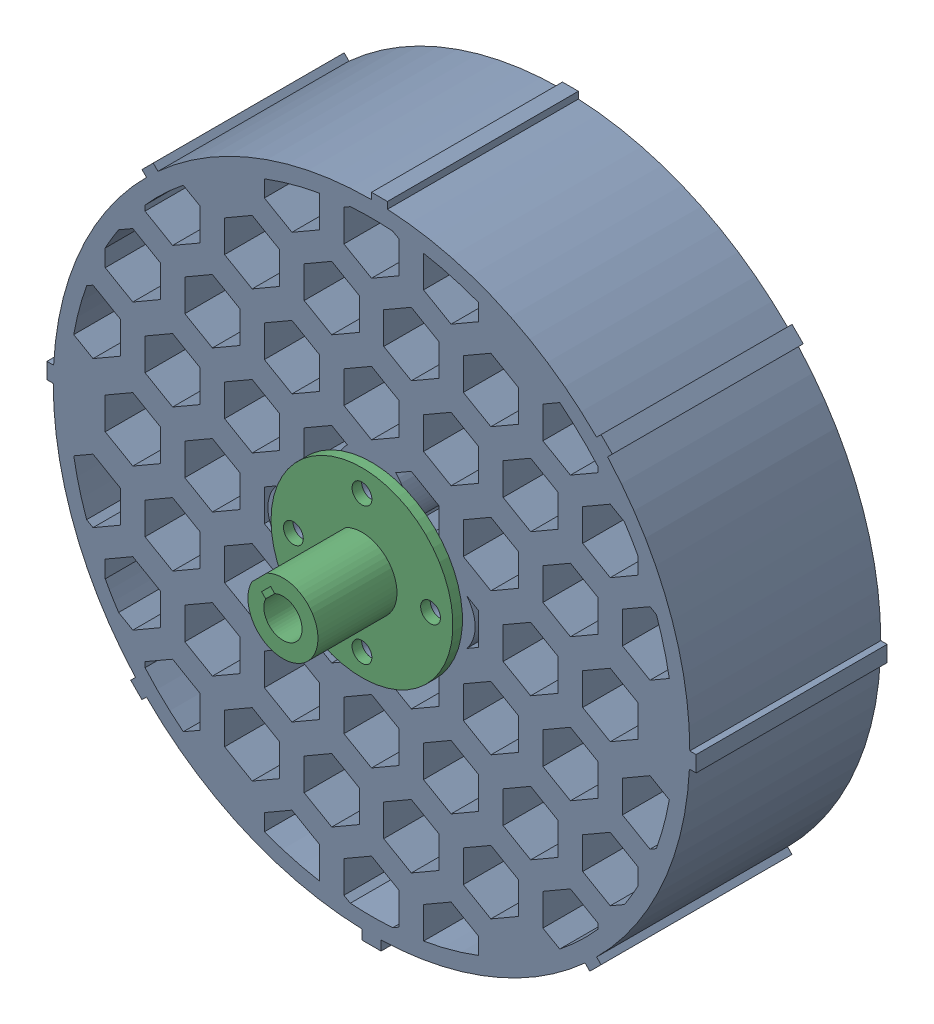
SolidWorks assembly Wheel Assy, configuration Default. Lengths in mm.
Overall size (204 204.97 90.82).
4 component instances, 4 part files, 9 mates.
Components (placement in the parent):
- wheel-1: wheel [Default] at origin size (204 204.97 60)
- bushing-1: bushing [Default] at origin size (55.77 55.77 63)
- cncmotorconnection-1: cncmotorconnection [Default] at origin size (57.15 57.15 27.82)
- endplate-1: endplate [Default] at (-95 -265 0) x (0 -1 0) z (0 0 1) size (55.77 55.77 3)
Mates (geometry in assembly coordinates):
- Concentric1: concentric: cylinder of wheel-1 through (-158.4525 -85 60) axis (0 0 -1) radius 6.341; cylinder of bushing-1 through (-158.4525 -85 60) axis (0 0 -1) radius 6.339
- Concentric2: concentric: cylinder of wheel-1 through (-201.5475 -85 60) axis (0 0 -1) radius 6.341; cylinder of bushing-1 through (-201.5475 -85 60) axis (0 0 -1) radius 6.339
- Coincident1: coincident aligned: plane of wheel-1 through (-180.0007 -83.9993 60) normal (0 0 1); plane of bushing-1 through (-180 -85 60) normal (0 0 1)
- Concentric3: concentric: cylinder of wheel-1 through (-201.5475 -85 60) axis (0 0 -1) radius 3.1125; cylinder of cncmotorconnection-1 through (-201.5475 -85 92.7554) axis (0 0 -1) radius 3.1125
- Concentric4: concentric: cylinder of wheel-1 through (-158.4525 -85 60) axis (0 0 -1) radius 3.1125; cylinder of cncmotorconnection-1 through (-158.4525 -85 92.7554) axis (0 0 -1) radius 3.1125
- Concentric5: concentric: cylinder of wheel-1 through (-180 -63.4525 0) axis (0 0 1) radius 3.1125; cylinder of endplate-1 through (-180 -63.4525 0) axis (0 0 -1) radius 3.1125
- Concentric6: concentric: cylinder of wheel-1 through (-158.4525 -85 0) axis (0 0 1) radius 3.1125; cylinder of endplate-1 through (-158.4525 -85 0) axis (0 0 -1) radius 3.1125
- Coincident2: coincident anti-aligned: plane of wheel-1 through (-180.0007 -83.9993 0) normal (0 0 -1); plane of endplate-1 through (-180 -85 0) normal (0 0 1)
- Coincident3: coincident anti-aligned: plane of wheel-1 through (-180.0007 -83.9993 60) normal (0 0 1); plane of cncmotorconnection-1 through (-180 -85 60) normal (0 0 -1)
